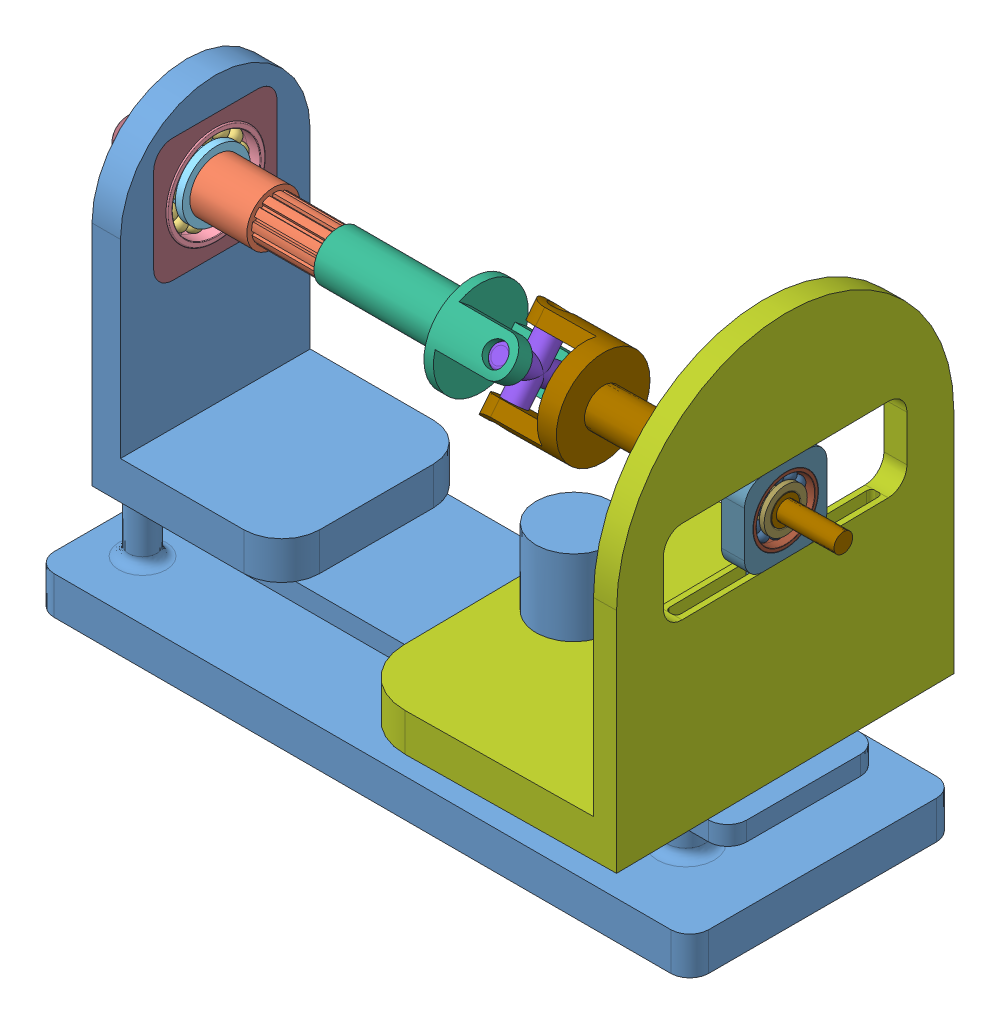
SolidWorks assembly Asamblare finala, configuration Default. Lengths in mm.
Overall size (354.35 260 181.74).
37 component instances, 14 part files, 21 mates.
Components (placement in the parent):
- Suport_1-1: Suport_1 [Default] at (-38.4157 54.0717 198.2778) x (1 0 0) z (0 1 0) size (345 140 220)
- Cilindru canelat-1: Cilindru canelat [Default] at (27.1843 174.0717 198.2778) x (0 0.934761 0.355277) z (-1 0 0) size (28 28 120)
- SKF_7205 BECBM-1: SKF_7205 BECBM [Default] at (-87.8157 174.0717 198.2778) size (15 52 52)
  - SKF_7205 BECBM_PART3-1: SKF_7205 BECBM_PART3 [Default] x (1 0 0) z (0 -0.464723 0.885456) size (7.94 7.94 7.94)
  - SKF_7205 BECBM_PART3-2: SKF_7205 BECBM_PART3 [Default] x (1 0 0) z (0 -0.822984 0.568065) size (7.94 7.94 7.94)
  - SKF_7205 BECBM_PART3-3: SKF_7205 BECBM_PART3 [Default] x (1 0 0) z (0 -0.992709 0.120537) size (7.94 7.94 7.94)
  - SKF_7205 BECBM_PART3-4: SKF_7205 BECBM_PART3 [Default] x (1 0 0) z (0 -0.935016 -0.354605) size (7.94 7.94 7.94)
  - SKF_7205 BECBM_PART3-5: SKF_7205 BECBM_PART3 [Default] x (1 0 0) z (0 -0.663123 -0.748511) size (7.94 7.94 7.94)
  - SKF_7205 BECBM_PART3-6: SKF_7205 BECBM_PART3 [Default] x (1 0 0) z (0 -0.239316 -0.970942) size (7.94 7.94 7.94)
  - SKF_7205 BECBM_PART3-7: SKF_7205 BECBM_PART3 [Default] x (1 0 0) z (0 0.239316 -0.970942) size (7.94 7.94 7.94)
  - SKF_7205 BECBM_PART3-8: SKF_7205 BECBM_PART3 [Default] x (1 0 0) z (0 0.663123 -0.748511) size (7.94 7.94 7.94)
  - SKF_7205 BECBM_PART3-9: SKF_7205 BECBM_PART3 [Default] x (1 0 0) z (0 0.935016 -0.354605) size (7.94 7.94 7.94)
  - SKF_7205 BECBM_PART3-10: SKF_7205 BECBM_PART3 [Default] x (1 0 0) z (0 0.992709 0.120537) size (7.94 7.94 7.94)
  - SKF_7205 BECBM_PART3-11: SKF_7205 BECBM_PART3 [Default] x (1 0 0) z (0 0.822984 0.568065) size (7.94 7.94 7.94)
  - SKF_7205 BECBM_PART3-12: SKF_7205 BECBM_PART3 [Default] x (1 0 0) z (0 0.464723 0.885456) size (7.94 7.94 7.94)
  - SKF_7205 BECBM_PART3-13: SKF_7205 BECBM_PART3 [Default] at origin size (7.94 7.94 7.94)
  - SKF_7205 BECBM_PART2-1: SKF_7205 BECBM_PART2 [Default] at origin size (15 52 52)
  - SKF_7205 BECBM_PART1-1: SKF_7205 BECBM_PART1 [Default] at origin size (15 35.85 35.85)
- Brat cruce canelat-1: Brat cruce canelat [Default] at (-8.4933 174.0717 198.2778) x (0 0.631888 0.775059) z (1 0 0) size (50 50 112)
- Suport_2-1: Suport_2 [Default] at (155.5053 74.0717 197.7762) x (0.999921 0 -0.012542) z (0 -1 0) size (140 180 210)
- Cruce cardanica-1: Cruce cardanica [Default] at (93.3323 191.1225 184.3767) x (0.999969 0.006143 -0.005008) z (0.007926 -0.775035 0.631868) size (12 44 44)
- Brat cruce iesire-3: Brat cruce iesire [Default] at (225.4963 174.0717 196.6223) x (-0.999921 0 0.012542) z (-0.00972 -0.631918 -0.774974) size (172 50 50)
- SKF_7202 BEGBP-2: SKF_7202 BEGBP [Default] at (214.4972 174.0717 196.7603) x (0.999921 0 -0.012542) z (0.012542 -0.007084 0.999896) size (11 35 35)
  - SKF_7202 BEGBP_PART3-1: SKF_7202 BEGBP_PART3 [Default] x (1 0 0) z (0 -0.587785 0.809017) size (6.35 6.35 6.35)
  - SKF_7202 BEGBP_PART3-2: SKF_7202 BEGBP_PART3 [Default] x (1 0 0) z (0 -0.951057 0.309017) size (6.35 6.35 6.35)
  - SKF_7202 BEGBP_PART3-3: SKF_7202 BEGBP_PART3 [Default] x (1 0 0) z (0 -0.951057 -0.309017) size (6.35 6.35 6.35)
  - SKF_7202 BEGBP_PART3-4: SKF_7202 BEGBP_PART3 [Default] x (1 0 0) z (0 -0.587785 -0.809017) size (6.35 6.35 6.35)
  - SKF_7202 BEGBP_PART3-5: SKF_7202 BEGBP_PART3 [Default] x (1 0 0) z (0 0 -1) size (6.35 6.35 6.35)
  - SKF_7202 BEGBP_PART3-6: SKF_7202 BEGBP_PART3 [Default] x (1 0 0) z (0 0.587785 -0.809017) size (6.35 6.35 6.35)
  - SKF_7202 BEGBP_PART3-7: SKF_7202 BEGBP_PART3 [Default] x (1 0 0) z (0 0.951057 -0.309017) size (6.35 6.35 6.35)
  - SKF_7202 BEGBP_PART3-8: SKF_7202 BEGBP_PART3 [Default] x (1 0 0) z (0 0.951057 0.309017) size (6.35 6.35 6.35)
  - SKF_7202 BEGBP_PART3-9: SKF_7202 BEGBP_PART3 [Default] x (1 0 0) z (0 0.587785 0.809017) size (6.35 6.35 6.35)
  - SKF_7202 BEGBP_PART3-10: SKF_7202 BEGBP_PART3 [Default] at origin size (6.35 6.35 6.35)
  - SKF_7202 BEGBP_PART2-1: SKF_7202 BEGBP_PART2 [Default] at origin size (11 35 35)
  - SKF_7202 BEGBP_PART1-1: SKF_7202 BEGBP_PART1 [Default] at origin size (11 23 23)
- Suport rulment intrare-3: Suport rulment intrare [Default] at (-73.4157 174.0717 198.2778) x (0 0 1) z (-1 0 0) size (65 65 25)
- Suport rulment iesire-2: Suport rulment iesire [Default] at (213.4972 174.0717 196.7728) x (-0.012542 0 -0.999921) z (0.999921 0 -0.012542) size (44 64 12)
Mates (geometry in assembly coordinates):
- Concentric1: concentric aligned: cylinder of Cilindru canelat-1 through (-92.8157 174.0717 198.2778) axis (1 0 0) radius 14; cylinder of SKF_7205 BECBM-1/SKF_7205 BECBM_PART1-1 through (-72.8157 174.0717 198.2778) axis (1 0 0) radius 12.5
- Coincident1: coincident anti-aligned: circle of Cilindru canelat-1; plane of SKF_7205 BECBM-1/SKF_7205 BECBM_PART1-1 through (-87.8157 158.35 182.8428) normal (-1 0 0)
- Concentric4: concentric aligned: cylinder of Cilindru canelat-1 through (-42.8157 174.0717 198.2778) axis (1 0 0) radius 11.5; cylinder of Brat cruce canelat-1 through (-8.4933 174.0717 198.2778) axis (1 0 0) radius 11.5
- Coincident3: coincident anti-aligned: plane of Cilindru canelat-1 through (-42.8157 174.7823 196.4083) normal (0 0.355277 -0.934761); plane of Brat cruce canelat-1 through (-8.4933 174.7823 196.4083) normal (0 -0.355277 0.934761)
- Concentric6: concentric anti-aligned: cylinder of Suport_1-1 through (115.5084 114.0717 198.2778) axis (0 -1 0) radius 20; cylinder of Suport_2-1 through (115.5084 54.0717 198.2778) axis (0 1 0) radius 20
- Coincident9: coincident aligned: circle of Brat cruce canelat-1; cylinder of Cruce cardanica-1 through (93.5067 187.9733 215.3291) axis (0 -0.631888 -0.775059) radius 6
- Width1: width anti-aligned: plane of Brat cruce canelat-1 through (93.5067 183.55 209.9037) normal (0 -0.631888 -0.775059); plane of Brat cruce canelat-1 through (93.5067 164.5934 186.6519) normal (0 0.631888 0.775059); plane of Cruce cardanica-1 through (93.5067 187.9733 215.3291) normal (0 0.631888 0.775059); plane of Cruce cardanica-1 through (93.5067 160.1702 181.2265) normal (0 -0.631888 -0.775059)
- Concentric8: concentric anti-aligned: cylinder of Brat cruce iesire-3 through (225.4963 174.0717 196.6223) axis (-0.999921 0 0.012542) radius 7.5; cylinder of SKF_7202 BEGBP-2/SKF_7202 BEGBP_PART1-1 through (225.4963 174.0717 196.6223) axis (0.999921 0 -0.012542) radius 7.5
- Coincident10: coincident anti-aligned: circle of Brat cruce iesire-3; plane of SKF_7202 BEGBP-2/SKF_7202 BEGBP_PART1-1 through (225.6395 162.1763 208.0374) normal (0.999921 0 -0.012542)
- Concentric10: concentric aligned: cylinder of Cruce cardanica-1 through (93.681 157.0209 212.1789) axis (-0.007926 0.775035 -0.631868) radius 6; cylinder of Brat cruce iesire-3 through (93.3878 185.6972 188.7998) axis (-0.007926 0.775035 -0.631868) radius 6
- Width3: width anti-aligned: plane of Brat cruce iesire-3 through (93.6256 162.4462 207.7559) normal (-0.007926 0.775035 -0.631868); plane of Brat cruce iesire-3 through (93.3878 185.6972 188.7998) normal (0.007926 -0.775035 0.631868); plane of Cruce cardanica-1 through (93.681 157.0209 212.1789) normal (0.007926 -0.775035 0.631868); plane of Cruce cardanica-1 through (93.3323 191.1225 184.3767) normal (-0.007926 0.775035 -0.631868)
- Coincident12: coincident: line of Suport_2-1 through (226.1896 152.0717 251.8939) axis (-0.012542 0 -0.999921); plane of SKF_7202 BEGBP-2/SKF_7202 BEGBP_PART2-1 through (225.7105 156.4308 213.6964) normal (0.999921 0 -0.012542)
- Coincident13: coincident anti-aligned: plane of Suport_1-1 through (-28.4157 54.0717 168.2778) normal (0 1 0); plane of Suport_2-1 through (155.5053 54.0717 197.7762) normal (0 -1 0)
- Coincident19: coincident anti-aligned: plane of Suport_1-1 through (-73.4157 196.5717 230.7778) normal (0 0 -1); plane of Suport rulment intrare-3 through (-88.4157 141.5717 230.7778) normal (0 0 1)
- Concentric17: concentric aligned: cylinder of SKF_7205 BECBM-1/SKF_7205 BECBM_PART2-1 through (-72.8157 174.0717 198.2778) axis (1 0 0) radius 26; cylinder of Suport rulment intrare-3 through (-88.4157 174.0717 198.2778) axis (1 0 0) radius 26
- Coincident20: coincident aligned: line of Suport_1-1 through (-73.4157 196.5717 165.7778) axis (0 -1 0); line of Suport rulment intrare-3 through (-73.4157 196.5717 165.7778) axis (0 -1 0)
- Coincident21: coincident anti-aligned: circle of SKF_7205 BECBM-1/SKF_7205 BECBM_PART2-1; circle of Suport rulment intrare-3
- Coincident22: coincident anti-aligned: plane of Suport_1-1 through (-73.4157 141.5717 220.7778) normal (0 1 0); plane of Suport rulment intrare-3 through (-88.4157 141.5717 165.7778) normal (0 -1 0)
- Concentric22: concentric anti-aligned: cylinder of SKF_7202 BEGBP-2/SKF_7202 BEGBP_PART2-1 through (225.4963 174.0717 196.6223) axis (0.999921 0 -0.012542) radius 17.5; cylinder of Suport rulment iesire-2 through (225.4963 174.0717 196.6223) axis (-0.999921 0 0.012542) radius 17.5
- Coincident25: coincident anti-aligned: plane of Suport_2-1 through (214.1905 196.0717 252.0444) normal (0 -1 0); plane of Suport rulment iesire-2 through (225.2204 196.0717 174.624) normal (0 1 0)
- Coincident26: coincident aligned: line of Suport_2-1 through (212.8109 196.0717 142.053) axis (0.012542 0 0.999921); line of Suport rulment iesire-2 through (213.3467 196.0717 184.7737) axis (0.012542 0 0.999921)
